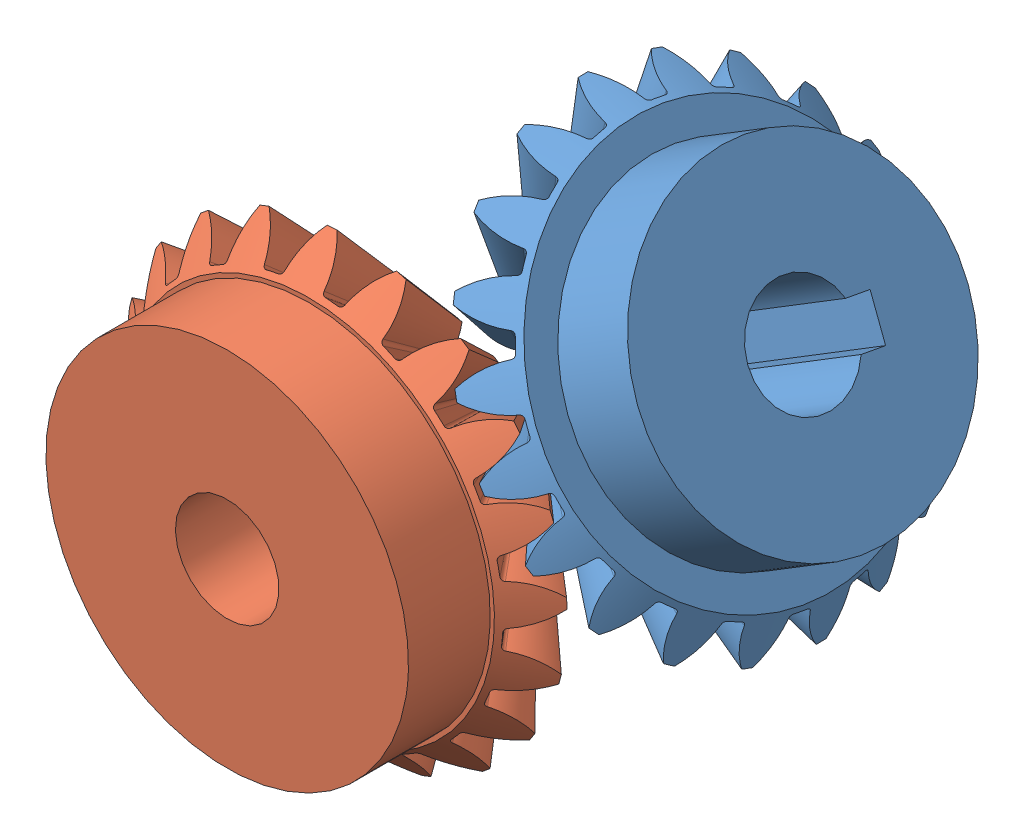
SolidWorks assembly Pinion Gear Syetem Arm2, configuration Default. Lengths in mm.
Overall size (61.52 59.61 54.17).
2 component instances, 2 part files, 4 mates.
Components (placement in the parent):
- straight bevel gear_am-1: straight bevel gear_am [Metric - Straight bevel gear 2M 20GT 20PT 20PA 12FW ---20O30H30MD10S1] at (-262.163 -1559.3749 -30.0001) x (-0.852169 -0.523267 0) z (0.517885 -0.843404 0.143055) size (19.85 42.67 42.67)
- straight bevel pinion_am-1: straight bevel pinion_am [Metric - Straight bevel pinion 2M20PT 20GT 20PA 12FW ---20O35H30MD10N] at (-280.9968 -1570.9396 -7.8991) x (0 0 -1) z (0.995257 -0.097283 0) size (19.85 42.67 42.67)
Mates (geometry in assembly coordinates):
- Coincident2: coincident: point of straight bevel gear_am-1; point of straight bevel pinion_am-1
- Perpendicular1: perpendicular: line of straight bevel gear_am-1 through (-253.6413 -1554.1422 -30.0001) axis (-0.852169 -0.523267 0); line of straight bevel pinion_am-1 through (-280.9968 -1570.9396 2.1009) axis (0 0 -1)
- Coincident4: coincident aligned: plane of straight bevel pinion_am-1 through (-280.9968 -1570.9396 0) normal (0 0 1)
- GearMate1: gear = 25.4 : 25.4 mm: cone of straight bevel gear_am-1 through (-270.1535 -1564.2814 -30.0001) axis (0.852169 0.523267 0); cone of straight bevel pinion_am-1 through (-280.9968 -1570.9396 -17.2758) axis (0 0 1)
